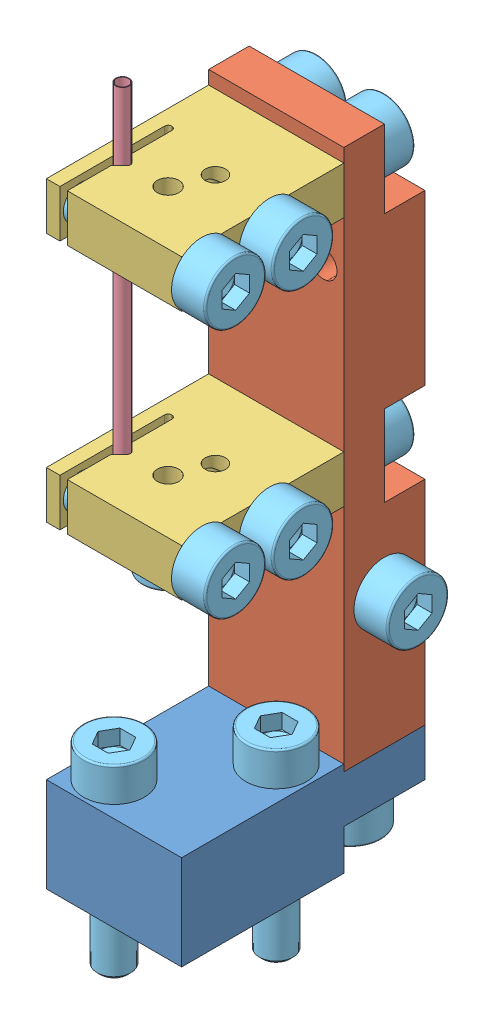
SolidWorks assembly OvenAssembly2, configuration Default. Lengths in mm.
Overall size (12.5 55.5 18.75).
35 component instances, 7 part files, 45 mates.
Components (placement in the parent):
- OvenBase2-1: OvenBase2 [Default] at (5.2062 4.9823 14.2147) size (10 7 18)
- OvenBack2-1: OvenBack2 [Default] at (5.2062 11.4823 8.2147) size (10 40 6)
- OvenSide2-1: OvenSide2 [Default] at (5.2062 46.9823 17.2147) x (0 0 1) z (-1 0 0) size (12 3.5 10)
- OvenSide2-2: OvenSide2 [Default] at (5.2062 28.4823 17.2147) x (0 0 1) z (-1 0 0) size (12 3.5 10)
- OvenTube2-1: OvenTube2 [Default] at (1.8269 28.4823 19.2147) x (0.998775 0 -0.049476) z (0.049476 0 0.998775) size (1 27 1)
- socket head cap screw_iso-10: socket head cap screw_iso [ISO 4762 M2.5 x 10 - 10N] at (12.7062 30.2323 21.7147) x (-1 0 0) z (0 0 -1) size (12.5 4.5 4.5)
- socket head cap screw_iso-12: socket head cap screw_iso [ISO 4762 M2.5 x 10 - 10N] at (12.7062 48.7323 21.7147) x (-1 0 0) z (0 0 -1) size (12.5 4.5 4.5)
- socket head cap screw_iso-17: socket head cap screw_iso [ISO 4762 M2.5 x 6 - 6N] at (7.7062 5.4823 8.2147) x (0 1 0) z (0 0 1) size (8.5 4.5 4.5)
- socket head cap screw_iso-18: socket head cap screw_iso [ISO 4762 M2.5 x 6 - 6N] at (2.7062 5.4823 8.2147) x (0 1 0) z (0 0 1) size (8.5 4.5 4.5)
- socket head cap screw_iso-19: socket head cap screw_iso [ISO 4762 M2.5 x 4 - 4N] at (12.7062 48.7323 16.7147) x (-1 0 0) z (0 0 -1) size (6.5 4.5 4.5)
- socket head cap screw_iso-20: socket head cap screw_iso [ISO 4762 M2.5 x 4 - 4N] at (12.7062 30.2323 16.7147) x (-1 0 0) z (0 0 -1) size (6.5 4.5 4.5)
- socket head cap screw_iso-21: socket head cap screw_iso [ISO 4762 M2.5 x 12 - 12N] at (2.7062 14.4823 20.7147) x (0 -1 0) z (0 0 1) size (14.5 4.5 4.5)
- socket head cap screw_iso-22: socket head cap screw_iso [ISO 4762 M2.5 x 12 - 12N] at (7.7062 14.4823 13.7147) x (0 -1 0) z (0 0 1) size (14.5 4.5 4.5)
- OvenBase2-2: OvenBase2 [Default] at (-5.7938 4.9823 14.2147) size (10 7 18) (hidden)
- OvenBack2-2: OvenBack2 [Default] at (-5.7938 11.4823 8.2147) size (10 40 6) (hidden)
- OvenSide2-4: OvenSide2 [Default] at (-5.7938 31.9823 17.2147) x (0 0 1) z (1 0 0) size (12 3.5 10) (hidden)
- OvenTube2-2: OvenTube2 [Default] at (-2.4145 28.4823 19.2147) x (-0.998775 0 -0.049476) z (0.049476 0 -0.998775) size (1 27 1) (hidden)
- socket head cap screw_iso-23: socket head cap screw_iso [ISO 4762 M2.5 x 10 - 10N] at (-13.2938 48.7323 21.7147) size (12.5 4.5 4.5) (hidden)
- socket head cap screw_iso-24: socket head cap screw_iso [ISO 4762 M2.5 x 10 - 10N] at (-13.2938 30.2323 21.7147) size (12.5 4.5 4.5) (hidden)
- socket head cap screw_iso-25: socket head cap screw_iso [ISO 4762 M2.5 x 6 - 6N] at (-8.2938 5.4823 8.2147) x (0 1 0) z (0 0 -1) size (8.5 4.5 4.5) (hidden)
- socket head cap screw_iso-26: socket head cap screw_iso [ISO 4762 M2.5 x 6 - 6N] at (-3.2938 5.4823 8.2147) x (0 1 0) z (0 0 -1) size (8.5 4.5 4.5) (hidden)
- socket head cap screw_iso-31: socket head cap screw_iso [ISO 4762 M2.5 x 4 - 4N] at (-13.2938 30.2323 16.7147) size (6.5 4.5 4.5) (hidden)
- socket head cap screw_iso-32: socket head cap screw_iso [ISO 4762 M2.5 x 4 - 4N] at (-13.2938 48.7323 16.7147) size (6.5 4.5 4.5) (hidden)
- socket head cap screw_iso-34: socket head cap screw_iso [ISO 4762 M2.5 x 4 - 4N] at (12.7062 21.4823 8.2147) x (-1 0 0) z (0 0 -1) size (6.5 4.5 4.5)
- socket head cap screw_iso-35: socket head cap screw_iso [ISO 4762 M2.5 x 4 - 4N] at (-13.2938 21.4823 8.2147) size (6.5 4.5 4.5) (hidden)
- socket head cap screw_iso-39: socket head cap screw_iso [ISO 4762 M2 x 3 - 3N] at (5.2062 25.8823 19.2147) x (0 1 0) z (0 0 1) size (5 3.8 3.8)
- plain washer 10673 type snl_iso-5: plain washer 10673 type snl_iso [ISO 10673-2.25-S] at (5.2062 28.4823 19.2147) x (0 -1 0) z (0 0 1) size (0.6 5 5)
- socket head cap screw_iso-40: socket head cap screw_iso [ISO 4762 M2 x 3 - 3N] at (-5.7938 25.8823 19.2147) x (0 1 0) z (0 0 -1) size (5 3.8 3.8) (hidden)
- plain washer 10673 type snl_iso-6: plain washer 10673 type snl_iso [ISO 10673-2.25-S] at (-5.7938 28.4823 19.2147) x (0 -1 0) z (0 0 -1) size (0.6 5 5) (hidden)
- OvenSide2-5: OvenSide2 [Default] at (-5.7938 50.4823 17.2147) x (0 0 1) z (1 0 0) size (12 3.5 10) (hidden)
- OvenStand-1: OvenStand [Default] at (5.2062 -5.0177 17.2147) size (40 10 40) (hidden)
- socket head cap screw_iso-41: socket head cap screw_iso [ISO 4762 M2.5 x 5 - 5N] at (7.7062 48.7323 5.7147) x (0 0 1) z (-1 0 0) size (7.5 4.5 4.5)
- socket head cap screw_iso-42: socket head cap screw_iso [ISO 4762 M2.5 x 5 - 5N] at (2.7062 48.7323 5.7147) x (0 0 1) z (-1 0 0) size (7.5 4.5 4.5)
- socket head cap screw_iso-43: socket head cap screw_iso [ISO 4762 M2.5 x 5 - 5N] at (7.7062 30.2323 5.7147) x (0 0 1) z (-1 0 0) size (7.5 4.5 4.5)
- socket head cap screw_iso-44: socket head cap screw_iso [ISO 4762 M2.5 x 5 - 5N] at (2.7062 30.2323 5.7147) x (0 0 1) z (-1 0 0) size (7.5 4.5 4.5)
Mates (geometry in assembly coordinates):
- Concentric1: concentric aligned: cylinder of OvenBase2-1 through (7.7062 7.9823 8.2147) axis (0 -1 0) radius 1.35; cylinder of OvenBack2-1 through (7.7062 11.4823 8.2147) axis (0 -1 0) radius 1.025
- Concentric2: concentric aligned: cylinder of OvenBase2-1 through (2.7062 7.9823 8.2147) axis (0 -1 0) radius 1.35; cylinder of OvenBack2-1 through (2.7062 11.4823 8.2147) axis (0 -1 0) radius 1.025
- Coincident1: coincident anti-aligned: plane of OvenBase2-1 through (5.2062 11.4823 14.2147) normal (0 1 0); plane of OvenBack2-1 through (5.2062 11.4823 8.2147) normal (0 -1 0)
- Concentric3: concentric aligned: cylinder of OvenBack2-1 through (7.7062 48.7323 5.2147) axis (0 0 -1) radius 1.35; cylinder of OvenSide2-1 through (7.7062 48.7323 11.2147) axis (0 0 -1) radius 1.025
- Parallel1: parallel aligned: cylinder of OvenBack2-1 through (2.7062 48.7323 5.2147) axis (0 0 -1) radius 1.35; cylinder of OvenSide2-1 through (2.7062 48.7323 11.2147) axis (0 0 -1) radius 1.025
- Coincident2: coincident anti-aligned: plane of OvenBack2-1 through (0.2062 51.4823 11.2147) normal (0 0 1); plane of OvenSide2-1 through (10.2062 50.4823 11.2147) normal (0 0 -1)
- Concentric5: concentric aligned: cylinder of OvenBack2-1 through (7.7062 30.2323 5.2147) axis (0 0 -1) radius 1.35; cylinder of OvenSide2-2 through (7.7062 30.2323 11.2147) axis (0 0 -1) radius 1.025
- Concentric6: concentric aligned: cylinder of OvenBack2-1 through (2.7062 30.2323 5.2147) axis (0 0 -1) radius 1.35; cylinder of OvenSide2-2 through (2.7062 30.2323 11.2147) axis (0 0 -1) radius 1.025
- Coincident3: coincident anti-aligned: plane of OvenBack2-1 through (0.2062 51.4823 11.2147) normal (0 0 1); plane of OvenSide2-2 through (10.2062 31.9823 11.2147) normal (0 0 -1)
- Tangent1: tangent anti-aligned: plane of OvenSide2-1 through (2.8701 46.9823 19.5507) normal (-0.707107 0 0.707107); cylinder of OvenTube2-1 through (1.8269 55.4823 19.2147) axis (0 -1 0) radius 0.5
- Coincident4: coincident aligned: plane of OvenSide2-2 through (5.2062 28.4823 17.2147) normal (0 -1 0); plane of OvenTube2-1 through (1.8269 28.4823 19.2147) normal (0 -1 0)
- Concentric171: concentric aligned: cylinder of OvenSide2-2 through (10.2062 30.2323 21.7147) axis (1 0 0) radius 1.35; cylinder of socket head cap screw_iso-10 through (44.4562 30.2323 21.7147) axis (1 0 0) radius 1.25
- Coincident141: coincident anti-aligned: plane of OvenSide2-2 through (10.2062 31.9823 11.2147) normal (1 0 0); plane of socket head cap screw_iso-10 through (10.2062 32.4823 21.7147) normal (-1 0 0)
- Concentric191: concentric aligned: cylinder of OvenSide2-1 through (10.2062 48.7323 21.7147) axis (1 0 0) radius 1.35; cylinder of socket head cap screw_iso-12 through (44.4562 48.7323 21.7147) axis (1 0 0) radius 1.25
- Coincident161: coincident anti-aligned: plane of OvenSide2-1 through (10.2062 50.4823 11.2147) normal (1 0 0); plane of socket head cap screw_iso-12 through (10.2062 50.9823 21.7147) normal (-1 0 0)
- Concentric241: concentric aligned: cylinder of OvenBase2-1 through (7.7062 7.9823 8.2147) axis (0 -1 0) radius 1.35; cylinder of socket head cap screw_iso-17 through (7.7062 -26.2677 8.2147) axis (0 -1 0) radius 1.25
- Coincident211: coincident anti-aligned: plane of OvenBase2-1 through (5.2062 7.9823 14.2147) normal (0 -1 0); plane of socket head cap screw_iso-17 through (5.4562 7.9823 8.2147) normal (0 1 0)
- Concentric251: concentric aligned: cylinder of OvenBase2-1 through (2.7062 7.9823 8.2147) axis (0 -1 0) radius 1.35; cylinder of socket head cap screw_iso-18 through (2.7062 -26.2677 8.2147) axis (0 -1 0) radius 1.25
- Coincident221: coincident anti-aligned: plane of OvenBase2-1 through (5.2062 7.9823 14.2147) normal (0 -1 0); plane of socket head cap screw_iso-18 through (0.4562 7.9823 8.2147) normal (0 1 0)
- Concentric261: concentric aligned: cylinder of OvenSide2-1 through (10.2062 48.7323 16.7147) axis (1 0 0) radius 1.025; cylinder of socket head cap screw_iso-19 through (44.4562 48.7323 16.7147) axis (1 0 0) radius 2.25
- Coincident231: coincident anti-aligned: plane of OvenSide2-1 through (10.2062 50.4823 11.2147) normal (1 0 0); plane of socket head cap screw_iso-19 through (10.2062 50.9823 16.7147) normal (-1 0 0)
- Concentric271: concentric aligned: cylinder of OvenSide2-2 through (10.2062 30.2323 16.7147) axis (1 0 0) radius 1.025; cylinder of socket head cap screw_iso-20 through (44.4562 30.2323 16.7147) axis (1 0 0) radius 2.25
- Coincident241: coincident anti-aligned: plane of OvenSide2-2 through (10.2062 31.9823 11.2147) normal (1 0 0); plane of socket head cap screw_iso-20 through (10.2062 32.4823 16.7147) normal (-1 0 0)
- Concentric281: concentric aligned: cylinder of OvenBase2-1 through (2.7062 11.9823 20.7147) axis (0 1 0) radius 1.35; cylinder of socket head cap screw_iso-21 through (2.7062 46.2323 20.7147) axis (0 1 0) radius 1.25
- Coincident251: coincident anti-aligned: plane of OvenBase2-1 through (5.2062 11.9823 14.2147) normal (0 1 0); plane of socket head cap screw_iso-21 through (4.9562 11.9823 20.7147) normal (0 -1 0)
- Concentric291: concentric aligned: cylinder of OvenBase2-1 through (7.7062 11.9823 13.7147) axis (0 1 0) radius 1.35; cylinder of socket head cap screw_iso-22 through (7.7062 46.2323 13.7147) axis (0 1 0) radius 1.25
- Coincident261: coincident anti-aligned: plane of OvenBase2-1 through (5.2062 11.9823 14.2147) normal (0 1 0); plane of socket head cap screw_iso-22 through (9.9562 11.9823 13.7147) normal (0 -1 0)
- Tangent2: tangent anti-aligned: plane of OvenSide2-1 through (4.8701 46.9823 16.8786) normal (-0.707107 0 -0.707107); cylinder of OvenTube2-1 through (1.8269 55.4823 19.2147) axis (0 -1 0) radius 0.5
- Concentric2931: concentric aligned: cylinder of OvenBack2-1 through (10.2062 21.4823 8.2147) axis (1 0 0) radius 1.025; cylinder of socket head cap screw_iso-34 through (44.4562 21.4823 8.2147) axis (1 0 0) radius 2.25
- Coincident2631: coincident anti-aligned: plane of OvenBack2-1 through (10.2062 51.4823 5.2147) normal (1 0 0); plane of socket head cap screw_iso-34 through (10.2062 23.7323 8.2147) normal (-1 0 0)
- Concentric317: concentric anti-aligned: cylinder of socket head cap screw_iso-39 through (5.2062 -5.8677 19.2147) axis (0 -1 0) radius 1.9; cylinder of plain washer 10673 type snl_iso-5 through (5.2062 27.8823 19.2147) axis (0 1 0) radius 1.125
- Coincident287: coincident anti-aligned: plane of OvenSide2-2 through (5.2062 28.4823 17.2147) normal (0 -1 0); plane of plain washer 10673 type snl_iso-5 through (5.2062 28.4823 19.2147) normal (0 1 0)
- Concentric3181: concentric aligned: cylinder of OvenSide2-2 through (5.2062 28.4823 19.2147) axis (0 -1 0) radius 0.8; cylinder of socket head cap screw_iso-39 through (5.2062 -5.8677 19.2147) axis (0 -1 0) radius 1.9
- Coincident2881: coincident anti-aligned: plane of socket head cap screw_iso-39 through (3.3062 27.8823 19.2147) normal (0 1 0); plane of plain washer 10673 type snl_iso-5 through (5.2062 27.8823 19.2147) normal (0 -1 0)
- Coincident2882: coincident anti-aligned: plane of OvenBase2-1 through (5.2062 4.9823 14.2147) normal (0 -1 0); plane of OvenStand-1 through (5.2062 4.9823 17.2147) normal (0 1 0)
- Concentric3182: concentric aligned: circle of OvenBase2-1; cylinder of OvenStand-1 through (2.7062 4.9823 20.7147) axis (0 1 0) radius 1.025
- Concentric3183: concentric aligned: circle of OvenBase2-1; cylinder of OvenStand-1 through (7.7062 4.9823 13.7147) axis (0 1 0) radius 1.025
- Concentric31841: concentric aligned: cylinder of OvenBack2-1 through (7.7062 48.7323 5.2147) axis (0 0 -1) radius 1.35; cylinder of socket head cap screw_iso-41 through (7.7062 48.7323 -26.0353) axis (0 0 -1) radius 1.25
- Coincident28831: coincident anti-aligned: plane of OvenBack2-1 through (5.2062 11.4823 8.2147) normal (0 0 -1); plane of socket head cap screw_iso-41 through (7.7062 50.9823 8.2147) normal (0 0 1)
- Concentric31851: concentric aligned: cylinder of OvenBack2-1 through (2.7062 48.7323 5.2147) axis (0 0 -1) radius 1.35; cylinder of socket head cap screw_iso-42 through (2.7062 48.7323 -26.0353) axis (0 0 -1) radius 1.25
- Coincident28841: coincident anti-aligned: plane of OvenBack2-1 through (5.2062 11.4823 8.2147) normal (0 0 -1); plane of socket head cap screw_iso-42 through (2.7062 50.9823 8.2147) normal (0 0 1)
- Concentric31861: concentric aligned: cylinder of OvenBack2-1 through (7.7062 30.2323 5.2147) axis (0 0 -1) radius 1.35; cylinder of socket head cap screw_iso-43 through (7.7062 30.2323 -26.0353) axis (0 0 -1) radius 1.25
- Coincident28851: coincident anti-aligned: plane of OvenBack2-1 through (5.2062 11.4823 8.2147) normal (0 0 -1); plane of socket head cap screw_iso-43 through (7.7062 32.4823 8.2147) normal (0 0 1)
- Concentric31871: concentric aligned: cylinder of OvenBack2-1 through (2.7062 30.2323 5.2147) axis (0 0 -1) radius 1.35; cylinder of socket head cap screw_iso-44 through (2.7062 30.2323 -26.0353) axis (0 0 -1) radius 1.25
- Coincident28861: coincident anti-aligned: plane of OvenBack2-1 through (5.2062 11.4823 8.2147) normal (0 0 -1); plane of socket head cap screw_iso-44 through (2.7062 32.4823 8.2147) normal (0 0 1)
